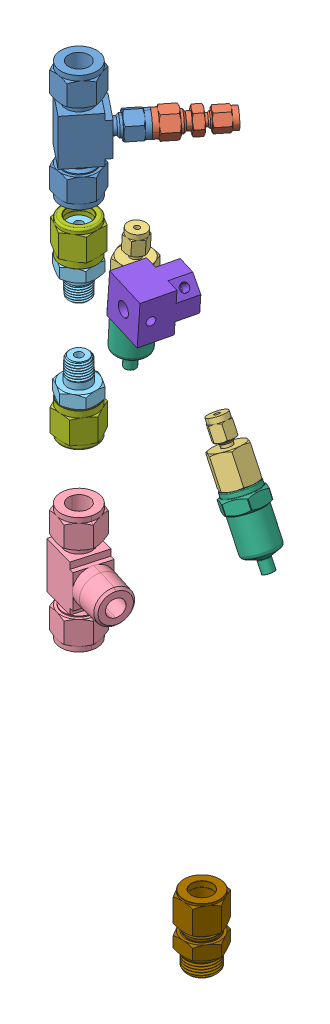
SolidWorks assembly BS2 Lower Fluids Assembly LOx, configuration Default. Lengths in mm.
Overall size (161.41 500.91 102.98).
19 component instances, 14 part files, 96 mates.
Components (placement in the parent):
- -8 MS -4MS -8MS Tee-1: -8 MS -4MS -8MS Tee [Default] at (-23.9548 1051.2282 52.2584) x (0 1 0) z (-0.624096 0 0.781347) size (72.14 22.35 44.65)
- -4 MS to -2 MS.stp-1: -4 MS to -2 MS.stp [Default] at (-4.1397 1087.2962 27.4506) x (0.624096 0 -0.781347) z (0.781347 0 0.624096) size (38.61 14.22 16.42)
- -2 MS to -4 FNPT-1: -2 MS to -4 FNPT [Default] at (38.4704 953.5373 29.1263) x (0.467448 -0.88319 0.038303) z (-0.038303 0.023053 0.999) size (33.53 19.05 22)
- -2 MS to -4 FNPT-2: -2 MS to -4 FNPT [Default] at (-56.112 983.757 -15.9203) x (-0.034482 -0.999152 0.022511) z (-0.575272 0.038262 0.817067) size (33.53 19.05 22)
- -8MS -8 MNPT -8MS Tee.stp-2: -8MS -8 MNPT -8MS Tee.stp [Default] at (-23.9548 886.0647 52.2584) x (0 -1 0) z (-0.962728 0 -0.27047) size (72.14 22.35 45.92)
- BallValve -8FNPT No handle-4: BallValve -8FNPT No handle [46495K21] at (21.8363 849.9967 65.123) x (0.028527 -0.994422 -0.10154) z (0.962728 0 0.27047) (suppressed, hidden)
- -8 MAN -8 MNPT-1: -8 MAN -8 MNPT [50715K116] at (-23.9548 1016.5413 52.2584) x (1 0 0) z (0 1 0) size (20.64 23.83 39.3)
- -8 MAN -8 MNPT-2: -8 MAN -8 MNPT [50715K116] at (-23.9548 946.1515 52.2584) x (1 0 0) z (0 -1 0) size (20.64 23.83 39.3)
- -8 Bottom Tank-1: -8 Bottom Tank [Default] at (-23.9548 863.2047 52.2584) x (0.033836 0 -0.999427) z (0.999427 0 0.033836) (suppressed, hidden)
- -8 Bottom Tank Post MV-1: -8 Bottom Tank Post MV [Default] at (-23.9548 1035.9882 52.2584) x (0.222246 0 -0.974991) z (0.974991 0 0.222246) (suppressed, hidden)
- PT -4MNPT-1: PT -4MNPT [Default] at (59.285 914.2106 30.8319) x (-0.467448 0.88319 -0.038303) z (0.475074 0.214432 -0.853418) size (56.32 25.42 22.23)
- PT -4MNPT-2: PT -4MNPT [Default] at (-57.6475 939.2668 -14.9179) x (0.034482 0.999152 -0.022511) z (0.950092 -0.025784 0.310902) size (56.32 25.42 22.23)
- Defined Kinetrol-2: Defined Kinetrol [Default] at (-4.5128 981.3338 -29.4755) x (-0.969139 0.091601 -0.228865) z (-0.229831 0 0.973231) (suppressed, hidden)
- -8 Bottom Tank to MV-1: -8 Bottom Tank to MV [Default] at (0 641.7628 0) x (0.909045 0 0.416698) z (-0.416698 0 0.909045) (suppressed, hidden)
- BallValve -8FNPT No handle-1: BallValve -8FNPT No handle [46495K21] at (-23.9548 981.3464 52.2584) x (-0.973231 0 -0.229831) z (0 -1 0) (suppressed, hidden)
- -8AN Al Nut-1: -8AN Al Nut [2227K63] at (-23.9548 1019.1924 52.2584) x (0.999966 0 -0.00829) z (0 1 0) size (22.23 25.66 21.56)
- -8AN Al Nut-4: -8AN Al Nut [2227K63] at (-23.9548 943.5004 52.2584) x (0.832606 0 0.553865) z (0 -1 0) size (22.23 25.66 21.56)
- kincon_2_0.75Inch-2: kincon_2_0.75Inch [Default] at (-11.3798 981.3464 -0.9912) x (-0.748323 -0.639362 -0.176718) z (-0.622247 0.768906 -0.146945) size (35.92 31.75 35.92)
- -8 Swage to ORB-1: -8 Swage to ORB [5182K867] at (0 664.6227 0) x (-0.837169 0 -0.546944) z (0 1 0) size (22.23 25.66 42.16)
Mates (geometry in assembly coordinates):
- Coincident12: coincident anti-aligned: cone of Recovery Complete CAD-1/Strength Test Drogue Pods-1 through (0 -2736.5654 0) axis (0 -1 0); circle of COTS Tangent Ogive Nose Cone with metal tip - 8 inch-1/Tangent_Ogive_Nosecone_01-1
- Concentric22: concentric aligned: cylinder of Upper Prop Skin-2 through (0 -990.6 0) axis (0 -1 0) radius 101.6; cylinder of Coupler-3 through (0 -1866.9 0) axis (0 -1 0) radius 98.425
- Concentric24: concentric aligned: cylinder of COPV skin-2 through (0 -1905 0) axis (0 -1 0) radius 101.6; cylinder of Upper Prop Skin-2 through (0 -990.6 0) axis (0 -1 0) radius 101.6
- Coincident21: coincident anti-aligned: plane of COPV skin-2 through (0 -1905 0) normal (0 1 0); plane of Upper Prop Skin-2 through (0 -1905 0) normal (0 -1 0)
- Distance2: distance = 38.1 mm aligned: plane of Upper Prop Skin-2 through (0 -1905 0) normal (0 -1 0); plane of Coupler-3 through (0 -1943.1 0) normal (0 -1 0)
- Tangent2: tangent anti-aligned: cylinder of Upper Prop Skin-2 through (0 -990.6 0) axis (0 -1 0) radius 101.6; plane of 92620A408_Zinc Yellow-Chromate Plated Hex Head Screw-1 through (47.7776 -954.5521 89.7332) normal (-0.5 0 -0.866025)
- Parallel3: parallel anti-aligned: cylinder of Upper Prop Skin-2 through (-143.466 -1885.95 7.9145) axis (0.998482 0 -0.055083) radius 1.5875; cylinder of Coupler-3 through (98.2756 -1885.95 -5.4215) axis (-0.998482 0 0.055083) radius 1.5875
- Concentric52: concentric anti-aligned: cylinder of BallValve -8FNPT No handle-1 through (-23.9548 995.8244 52.2584) axis (0 -1 0) radius 6.35; cylinder of -8FS -8MAN-1 through (-143.6616 977.0926 222.6164) axis (0 -1 0) radius 4.9657
- Coincident46: coincident anti-aligned: plane of BallValve -8FNPT No handle-1 through (-23.9548 1011.3184 52.2584) normal (0 1 0); plane of -8FS -8MAN-1 through (-143.3874 1004.2706 209.7877) normal (0 1 0)
- Coincident47: coincident aligned: circle of -8FS -8MAN-1; cone of -8AN Al Nut-1 through (-23.9548 1019.1924 52.2584) axis (0 -1 0)
- Concentric59: concentric aligned: cylinder of BallValve -8FNPT No handle-2 through (89.6282 874.3013 -241.9648) axis (0.042846 0.996573 -0.070751) radius 6.35; cylinder of -8FS -8MAN-3 through (103.855 914.3674 -250.7408) axis (-0.007638 0.99997 0.001301) radius 4.9657
- Coincident59: coincident anti-aligned: plane of BallValve -8FNPT No handle-2 through (94.7432 919.527 -230.0938) normal (0.042846 0.996573 -0.070751); plane of -8FS -8MAN-3 through (107.2777 887.2309 -263.1983) normal (0.007638 -0.99997 -0.001301)
- Coincident60: coincident anti-aligned: plane of BallValve -8FNPT No handle-2 through (88.9643 858.8604 -240.8686) normal (-0.042846 -0.996573 0.070751); plane of -8FS -8MAN-2 through (104.8256 827.267 -263.682) normal (-0.007638 0.99997 0.001301)
- Concentric60: concentric anti-aligned: cylinder of BallValve -8FNPT No handle-2 through (89.6282 874.3013 -241.9648) axis (0.042846 0.996573 -0.070751) radius 6.35; cylinder of -8FS -8MAN-2 through (104.7279 800.0708 -250.8894) axis (0.007638 -0.99997 -0.001301) radius 4.9657
- Concentric61: concentric anti-aligned: cylinder of -8AN Al Nut-2 through (88.6269 851.0134 -240.3115) axis (0.042846 0.996573 -0.070751) radius 8.7517; cylinder of -8FS -8MAN-2 through (104.7279 800.0708 -250.8894) axis (0.007638 -0.99997 -0.001301) radius 4.9657
- Concentric62: concentric anti-aligned: cylinder of -8AN Al Nut-3 through (91.8701 926.4461 -245.6668) axis (-0.042846 -0.996573 0.070751) radius 8.7517; cylinder of -8FS -8MAN-3 through (103.855 914.3674 -250.7408) axis (-0.007638 0.99997 0.001301) radius 4.9657
- Coincident61: coincident anti-aligned: plane of -8AN Al Nut-3 through (82.9788 926.1718 -254.9145) normal (-0.042846 -0.996573 0.070751); plane of -8FS -8MAN-3 through (107.2214 894.5967 -263.1887) normal (-0.007638 0.99997 0.001301)
- Coincident62: coincident anti-aligned: circle of -8AN Al Nut-2; cone of -8FS -8MAN-2 through (104.5727 820.3905 -250.863) axis (0.007638 -0.99997 -0.001301)
- Concentric68: concentric anti-aligned: cylinder of BallValve -8FNPT No handle-1 through (-23.9548 995.8244 52.2584) axis (0 -1 0) radius 6.35; cylinder of -8FS -8MAN-4 through (-143.6616 1044.4026 222.6164) axis (0 -1 0) radius 4.9657
- Coincident64: coincident aligned: plane of BallValve -8FNPT No handle-1 through (-20.4192 951.3744 37.2869) normal (0 -1 0); circle of -8FS -8MAN-4
- Concentric69: concentric aligned: cylinder of -8AN Al Nut-4 through (-23.9548 943.5004 52.2584) axis (0 1 0) radius 8.7517; cylinder of -8FS -8MAN-4 through (-143.6616 1044.4026 222.6164) axis (0 -1 0) radius 4.9657
- Coincident65: coincident anti-aligned: plane of -8AN Al Nut-4 through (-31.0618 943.5004 62.9421) normal (0 1 0); plane of -8FS -8MAN-4 through (-138.8376 1071.5806 210.7261) normal (0 1 0)
- Concentric72: concentric aligned: circle of BallValve -8FNPT No handle-2; circle of kincon_2_0.75Inch-1
- Coincident85: coincident anti-aligned: plane of BallValve -8FNPT No handle-2 through (94.7957 884.407 -220.1681) normal (0.208698 0.060326 0.976118); plane of kincon_2_0.75Inch-1 through (95.0411 890.1151 -220.5733) normal (-0.208698 -0.060326 -0.976118)
- Concentric73: concentric aligned: circle of BallValve -8FNPT No handle-1; circle of kincon_2_0.75Inch-2
- Coincident86: coincident anti-aligned: plane of BallValve -8FNPT No handle-1 through (-18.6769 987.0741 29.9089) normal (0.229831 0 -0.973231); plane of kincon_2_0.75Inch-2 through (-18.6769 981.3464 29.9089) normal (-0.229831 0 0.973231)
- Tangent3: tangent anti-aligned: cylinder of Upper Prop Skin-2 through (0 -990.6 0) axis (0 -1 0) radius 101.6; plane of 92220A183_Alloy Steel Low-Profile Socket Head Screw-1 through (89.7349 -1004.0731 47.69) normal (-0.892252 0 -0.451538)
- Coincident103: coincident anti-aligned: line of Defined Kinetrol-2 through (-8.5702 981.4187 12.7216) axis (-0.622247 0.768906 -0.146945); line of kincon_2_0.75Inch-2 through (-12.7344 986.5644 11.7382) axis (0.622247 -0.768906 0.146945)
- Concentric84: concentric aligned: cylinder of -8AN Al Tee-1 through (144.1547 917.8727 -221.5336) axis (0 0 -1) radius 4.9657; cylinder of -8AN Al Nut-5 through (144.1547 917.8727 -281.7376) axis (0 0 -1) radius 8.7517
- Concentric89: concentric anti-aligned: cylinder of BallValve -8FNPT No handle-3 through (144.457 782.0311 -215.5778) axis (-0.94691 0.017922 -0.320998) radius 6.35; cylinder of -8MS -8 MNPT -8MS Tee.stp-1 through (107.5778 782.7291 -228.0797) axis (0.94691 -0.017922 0.320998) radius 5.207
- Coincident109: coincident aligned: cone of BallValve -8FNPT No handle-3 through (117.0383 782.5501 -224.8726) axis (0.94691 -0.017922 0.320998); cone of -8MS -8 MNPT -8MS Tee.stp-1 through (116.1419 782.567 -225.1765) axis (0.94691 -0.017922 0.320998)
- Concentric90: concentric aligned: cylinder of -8 Al Top Tank to MV-1 through (82.8344 716.2834 -230.7465) axis (0.042846 0.996573 -0.070751) radius 6.35; cylinder of -8MS -8 MNPT -8MS Tee.stp-1 through (84.6533 758.5895 -233.7499) axis (0.042846 0.996573 -0.070751) radius 6.35
- Concentric91: concentric aligned: cylinder of -8 Bottom Tank to MV-1 through (-23.9548 785.9887 52.2584) axis (0 1 0) radius 6.35; cylinder of -8MS -8 MNPT -8MS Tee.stp-2 through (-23.9548 825.3587 52.2584) axis (0 1 0) radius 6.35
- Coincident110: coincident anti-aligned: plane of -8 Bottom Tank to MV-1 through (-23.9548 836.7887 52.2584) normal (0 1 0); plane of -8MS -8 MNPT -8MS Tee.stp-2 through (-23.9548 836.7887 52.2584) normal (0 -1 0)
- Coincident111: coincident aligned: cone of -8MS -8 MNPT -8MS Tee.stp-2 through (6.9866 849.9967 60.9511) axis (0.962728 0 0.27047); cone of BallValve -8FNPT No handle-4 through (7.8979 849.9967 61.2071) axis (0.962728 0 0.27047)
- Concentric92: concentric anti-aligned: cylinder of -8AN Al Nut-4 through (-23.9548 943.5004 52.2584) axis (0 1 0) radius 8.7517; cylinder of -8 MAN -8 MNPT-2 through (-23.9548 926.7047 52.2584) axis (0 -1 0) radius 2.413
- Concentric93: concentric aligned: cylinder of BallValve -8FNPT No handle-1 through (-23.9548 995.8244 52.2584) axis (0 -1 0) radius 6.35; cylinder of -8 MAN -8 MNPT-2 through (-23.9548 926.7047 52.2584) axis (0 -1 0) radius 2.413
- Coincident114: coincident anti-aligned: plane of -8AN Al Nut-4 through (-31.0618 943.5004 62.9421) normal (0 1 0); plane of -8 MAN -8 MNPT-2 through (-23.9548 943.5004 60.4461) normal (0 -1 0)
- Coincident115: coincident anti-aligned: plane of BallValve -8FNPT No handle-1 through (-20.4192 951.3744 37.2869) normal (0 -1 0); plane of -8 MAN -8 MNPT-2 through (-23.9548 951.3744 62.5771) normal (0 1 0)
- Coincident117: coincident anti-aligned: plane of BallValve -8FNPT No handle-1 through (-23.9548 1011.3184 52.2584) normal (0 1 0); plane of -8 MAN -8 MNPT-1 through (-23.9548 1011.3184 41.9396) normal (0 -1 0)
- Concentric95: concentric anti-aligned: cylinder of BallValve -8FNPT No handle-1 through (-23.9548 995.8244 52.2584) axis (0 -1 0) radius 6.35; cylinder of -8 MAN -8 MNPT-1 through (-23.9548 1035.9882 52.2584) axis (0 1 0) radius 2.413
- Coincident118: coincident anti-aligned: plane of -8AN Al Nut-1 through (-24.0612 1019.1924 39.4272) normal (0 -1 0); plane of -8 MAN -8 MNPT-1 through (-23.9548 1019.1924 44.0707) normal (0 1 0)
- Concentric96: concentric anti-aligned: cylinder of -8AN Al Nut-1 through (-23.9548 1019.1924 52.2584) axis (0 -1 0) radius 8.7517; cylinder of -8 MAN -8 MNPT-1 through (-23.9548 1035.9882 52.2584) axis (0 1 0) radius 2.413
- Coincident119: coincident anti-aligned: plane of BallValve -8FNPT No handle-2 through (94.7432 919.527 -230.0938) normal (0.042846 0.996573 -0.070751); plane of -8 MAN -8 MNPT-4 through (91.5935 917.8657 -255.4022) normal (-0.042846 -0.996573 0.070751)
- Coincident120: coincident anti-aligned: plane of BallValve -8FNPT No handle-2 through (88.9643 858.8604 -240.8686) normal (-0.042846 -0.996573 0.070751); plane of -8 MAN -8 MNPT-3 through (94.5107 858.0072 -249.528) normal (0.042846 0.996573 -0.070751)
- Concentric97: concentric anti-aligned: cylinder of BallValve -8FNPT No handle-2 through (89.6282 874.3013 -241.9648) axis (0.042846 0.996573 -0.070751) radius 6.35; cylinder of -8 MAN -8 MNPT-3 through (87.9073 834.2752 -239.1232) axis (-0.042846 -0.996573 0.070751) radius 2.413
- Concentric98: concentric aligned: cylinder of BallValve -8FNPT No handle-2 through (89.6282 874.3013 -241.9648) axis (0.042846 0.996573 -0.070751) radius 6.35; cylinder of -8 MAN -8 MNPT-4 through (92.5897 943.1843 -246.8551) axis (0.042846 0.996573 -0.070751) radius 2.413
- Concentric99: concentric anti-aligned: cylinder of -8AN Al Nut-2 through (88.6269 851.0134 -240.3115) axis (0.042846 0.996573 -0.070751) radius 8.7517; cylinder of -8 MAN -8 MNPT-3 through (87.9073 834.2752 -239.1232) axis (-0.042846 -0.996573 0.070751) radius 2.413
- Concentric100: concentric anti-aligned: cylinder of -8AN Al Nut-3 through (91.8701 926.4461 -245.6668) axis (-0.042846 -0.996573 0.070751) radius 8.7517; cylinder of -8 MAN -8 MNPT-4 through (92.5897 943.1843 -246.8551) axis (0.042846 0.996573 -0.070751) radius 2.413
- Coincident121: coincident anti-aligned: plane of -8AN Al Nut-3 through (82.9788 926.1718 -254.9145) normal (-0.042846 -0.996573 0.070751); plane of -8 MAN -8 MNPT-4 through (91.9184 925.8642 -253.8337) normal (0.042846 0.996573 -0.070751)
- Coincident122: coincident anti-aligned: plane of -8AN Al Nut-2 through (98.1003 849.9959 -248.9063) normal (0.042846 0.996573 -0.070751); plane of -8 MAN -8 MNPT-3 through (93.0279 850.3364 -247.1826) normal (-0.042846 -0.996573 0.070751)
- Concentric101: concentric aligned: cylinder of -8MS -8 MNPT -8MS Tee.stp-1 through (86.7646 807.6966 -237.2363) axis (-0.042846 -0.996573 0.070751) radius 6.35; cylinder of -8 Top Tank Fill to MV-1 through (87.9073 834.2752 -239.1232) axis (-0.042846 -0.996573 0.070751) radius 5.9808
- Coincident124: coincident anti-aligned: plane of -8 Al Top Tank to MV-1 through (85.143 769.9803 -234.5586) normal (0.042846 0.996573 -0.070751); plane of -8MS -8 MNPT -8MS Tee.stp-1 through (85.143 769.9803 -234.5586) normal (-0.042846 -0.996573 0.070751)
- Coincident127: coincident anti-aligned: plane of -8MS -8 MNPT -8MS Tee.stp-1 through (86.2748 796.3058 -236.4276) normal (0.042846 0.996573 -0.070751); plane of -8 Top Tank Fill to MV-1 through (86.2748 796.3058 -236.4276) normal (-0.042846 -0.996573 0.070751)
- Concentric102: concentric anti-aligned: cylinder of -8AN Al Nut-2 through (88.6269 851.0134 -240.3115) axis (0.042846 0.996573 -0.070751) radius 7.239; cylinder of -8 Top Tank Fill to MV-1 through (87.9073 834.2752 -239.1232) axis (-0.042846 -0.996573 0.070751) radius 5.9808
- Concentric103: concentric anti-aligned: cylinder of -8MS -8 MNPT -8MS Tee.stp-2 through (-23.9548 874.6347 52.2584) axis (0 -1 0) radius 6.35; cylinder of -8 Bottom Tank-1 through (-23.9548 863.2047 52.2584) axis (0 1 0) radius 5.9805
- Coincident129: coincident anti-aligned: plane of -8MS -8 MNPT -8MS Tee.stp-2 through (-23.9548 863.2047 52.2584) normal (0 1 0); plane of -8 Bottom Tank-1 through (-23.9548 863.2047 52.2584) normal (0 -1 0)
- Concentric104: concentric anti-aligned: cylinder of -8 MAN -8 MNPT-2 through (-23.9548 926.7047 52.2584) axis (0 -1 0) radius 2.413; cylinder of -8 Bottom Tank-1 through (-23.9548 863.2047 52.2584) axis (0 1 0) radius 5.9805
- Coincident130: coincident anti-aligned: plane of -8 MAN -8 MNPT-2 through (-23.9548 926.7047 54.6714) normal (0 -1 0); plane of -8 Bottom Tank-1 through (-23.9548 926.7047 52.2584) normal (0 1 0)
- Coincident131: coincident anti-aligned: line of Defined Kinetrol-2 through (-14.0831 975.5845 11.4197) axis (0.748323 0.639362 0.176718); line of kincon_2_0.75Inch-2 through (-9.2203 979.7391 12.5681) axis (-0.748323 -0.639362 -0.176718)
- Coincident142: coincident anti-aligned: line of Defined Kinetrol-1 through (104.6495 890.9129 -203.1609) axis (-0.632602 -0.752842 0.18178); line of kincon_2_0.75Inch-1 through (100.5387 886.0208 -201.9796) axis (0.632602 0.752842 -0.18178)
- Coincident141: coincident anti-aligned: line of Defined Kinetrol-1 through (98.8898 885.3922 -201.5882) axis (-0.745828 0.655431 0.118955); line of kincon_2_0.75Inch-1 through (93.8986 889.7784 -200.7922) axis (0.745828 -0.655431 -0.118955)
- Concentric105: concentric anti-aligned: cylinder of -8AN Al Nut-3 through (91.8701 926.4461 -245.6668) axis (-0.042846 -0.996573 0.070751) radius 8.7517; cylinder of -8FS -8MAN-5 through (-18.2973 1099.6198 -57.8209) axis (-0.006569 0.999978 0.001061) radius 8.322
- Coincident144: coincident anti-aligned: plane of -8 MAN -8 MNPT-3 through (89.2043 834.0757 -241.1482) normal (-0.042846 -0.996573 0.070751); plane of -8 Top Tank Fill to MV-1 through (87.9073 834.2752 -239.1232) normal (0.042846 0.996573 -0.070751)
- Concentric106: concentric anti-aligned: cylinder of -8 MAN -8 MNPT-4 through (92.5897 943.1843 -246.8551) axis (0.042846 0.996573 -0.070751) radius 2.413; cylinder of -8 Top Tank Post MV-1 through (96.9429 1044.4361 -254.0434) axis (-0.042846 -0.996573 0.070751) radius 6.35
- Coincident145: coincident anti-aligned: plane of -8 MAN -8 MNPT-4 through (92.6039 943.0128 -249.262) normal (0.042846 0.996573 -0.070751); plane of -8 Top Tank Post MV-1 through (92.5897 943.1843 -246.8551) normal (-0.042846 -0.996573 0.070751)
- Concentric107: concentric aligned: cylinder of -8 MAN -8 MNPT-1 through (-23.9548 1035.9882 52.2584) axis (0 1 0) radius 2.413; cylinder of -8 Bottom Tank Post MV-1 through (-23.9548 1035.9882 52.2584) axis (0 1 0) radius 6.35
- Coincident146: coincident anti-aligned: plane of -8 MAN -8 MNPT-1 through (-23.9548 1035.9882 49.8454) normal (0 1 0); plane of -8 Bottom Tank Post MV-1 through (-23.9548 1035.9882 52.2584) normal (0 -1 0)
- Concentric108: concentric aligned: cylinder of -8 Top Tank Post MV-1 through (96.9429 1044.4361 -254.0434) axis (-0.042846 -0.996573 0.070751) radius 6.35; cylinder of -8s Tee-2 through (-17.8835 1036.6403 -57.8877) axis (0.006569 -0.999978 -0.001061) radius 6.35
- Concentric109: concentric anti-aligned: cylinder of -8 Bottom Tank Post MV-1 through (-23.9548 1035.9882 52.2584) axis (0 1 0) radius 6.35; cylinder of -8s Tee-1 through (-23.9548 1051.2282 52.2584) axis (0 -1 0) radius 6.35
- Coincident149: coincident anti-aligned: plane of -8 Bottom Tank Post MV-1 through (-23.9548 1074.0882 52.2584) normal (0 1 0); plane of -8s Tee-1 through (-20.4836 1074.0882 57.5756) normal (0 -1 0)
- Concentric110: concentric anti-aligned: cylinder of -8 MS to -4 FNPT.stp-2 through (-74.7768 930.2968 -13.754) axis (0.034482 0.999152 -0.022511) radius 6.35; cylinder of PT -4MNPT-2 through (-56.7509 965.2447 -15.5032) axis (-0.034482 -0.999152 0.022511) radius 6.858
- Coincident150: coincident anti-aligned: plane of -8 MS to -4 FNPT.stp-2 through (-73.9532 918.9573 -8.0435) normal (-0.034482 -0.999152 0.022511); plane of PT -4MNPT-2 through (-57.2682 950.2574 -15.1656) normal (0.034482 0.999152 -0.022511)
- Concentric111: concentric anti-aligned: cylinder of -8 MS to -4 FNPT.stp-1 through (48.2965 933.7955 30.9286) axis (-0.467448 0.88319 -0.038303) radius 6.35; cylinder of PT -4MNPT-1 through (47.1313 937.1736 29.836) axis (0.467448 -0.88319 0.038303) radius 6.858
- Coincident151: coincident anti-aligned: plane of -8 MS to -4 FNPT.stp-1 through (50.9847 922.5024 36.1353) normal (0.467448 -0.88319 0.038303); plane of PT -4MNPT-1 through (54.143 923.9257 30.4105) normal (-0.467448 0.88319 -0.038303)
- Concentric112: concentric aligned: cylinder of -8s Tee-2 through (-21.1752 1072.6493 -21.9111) axis (-0.084693 -0.001613 0.996406) radius 6.35; cylinder of -8 MV to PT-1 through (-19.2391 1072.6862 -44.6889) axis (-0.084693 -0.001613 0.996406) radius 5.969
- Coincident152: coincident anti-aligned: plane of -8 Top Tank Post MV-1 through (96.9429 1044.4361 -254.0434) normal (0.042846 0.996573 -0.070751); plane of -8s Tee-2 through (-17.4959 1059.51 -64.1907) normal (0.006569 -0.999978 -0.001061)
- Coincident153: coincident anti-aligned: plane of -8s Tee-2 through (-19.1974 1066.3363 -44.6957) normal (-0.084693 -0.001613 0.996406); plane of -8 MV to PT-1 through (-19.2391 1072.6862 -44.6889) normal (0.084693 0.001613 -0.996406)
- Concentric113: concentric aligned: cone of -8 MS to -4 FNPT.stp-1 through (37.3669 954.4458 30.033) axis (0.467448 -0.88319 0.038303); cylinder of -8 MV to PT-1 through (-7.3451 1038.924 26.3693) axis (0.467448 -0.88319 0.038303) radius 6.35
- Coincident154: coincident anti-aligned: plane of -8 MS to -4 FNPT.stp-1 through (40.1476 949.1918 30.2609) normal (-0.467448 0.88319 -0.038303); plane of -8 MV to PT-1 through (40.1476 949.1918 30.2609) normal (0.467448 -0.88319 0.038303)
- Concentric115: concentric aligned: cone of -8 MS to -4 FNPT.stp-2 through (-73.9705 953.6584 -14.2803) axis (-0.034482 -0.999152 0.022511); cylinder of -8 MV to PT-2 through (-70.6723 1049.2285 -16.4335) axis (-0.034482 -0.999152 0.022511) radius 6.35
- Coincident156: coincident anti-aligned: plane of -8 MS to -4 FNPT.stp-2 through (-74.1756 947.7147 -14.1464) normal (0.034482 0.999152 -0.022511); plane of -8 MV to PT-2 through (-74.1756 947.7147 -14.1464) normal (-0.034482 -0.999152 0.022511)
- Concentric119: concentric aligned: cylinder of -8s Tee-1 through (-43.6714 1087.2962 22.0565) axis (-0.54665 0 -0.837361) radius 6.35; cylinder of -8 MV to PT-2 through (-31.175 1087.2962 41.1985) axis (-0.54665 0 -0.837361) radius 6.35
- Coincident157: coincident anti-aligned: plane of -8s Tee-1 through (-31.175 1080.9462 41.1985) normal (-0.54665 0 -0.837361); plane of -8 MV to PT-2 through (-31.175 1087.2962 41.1985) normal (0.54665 0 0.837361)
- Concentric122: concentric aligned: cylinder of -8 Bottom Tank Post MV-1 through (-23.9548 1035.9882 52.2584) axis (0 1 0) radius 6.35; cylinder of -8 MS -4MS -8MS Tee-1 through (-23.9548 1062.6582 52.2584) axis (0 1 0) radius 6.35
- Coincident158: coincident anti-aligned: plane of -8 Bottom Tank Post MV-1 through (-23.9548 1074.0882 52.2584) normal (0 1 0); plane of -8 MS -4MS -8MS Tee-1 through (-23.9548 1074.0882 52.2584) normal (0 -1 0)
- Concentric123: concentric anti-aligned: cylinder of -8 Top Tank Post MV-1 through (96.9429 1044.4361 -254.0434) axis (-0.042846 -0.996573 0.070751) radius 6.35; cylinder of -8 MS -4MS -8MS Tee-2 through (96.4532 1033.0453 -253.2347) axis (0.042846 0.996573 -0.070751) radius 6.35
- Coincident159: coincident anti-aligned: plane of -8 Top Tank Post MV-1 through (96.9429 1044.4361 -254.0434) normal (0.042846 0.996573 -0.070751); plane of -8 MS -4MS -8MS Tee-2 through (96.9429 1044.4361 -254.0434) normal (-0.042846 -0.996573 0.070751)
- Coincident160: coincident anti-aligned: plane of -8 MS -4MS -8MS Tee-1 through (-4.1397 1083.7402 27.4506) normal (0.624096 0 -0.781347); plane of -4 MS to -2 MS.stp-1 through (-1.3613 1087.2962 29.6699) normal (-0.624096 0 0.781347)
- Concentric124: concentric anti-aligned: cylinder of -8 MS -4MS -8MS Tee-1 through (-8.8954 1087.2962 33.4045) axis (-0.624096 0 0.781347) radius 3.175; cylinder of -4 MS to -2 MS.stp-1 through (0.6159 1087.2962 21.4967) axis (0.624096 0 -0.781347) radius 3.175
- Concentric126: concentric anti-aligned: cylinder of PT -4MNPT-1 through (47.1313 937.1736 29.836) axis (0.467448 -0.88319 0.038303) radius 6.858; cone of -2 MS to -4 FNPT-1 through (51.5372 928.8491 30.197) axis (-0.467448 0.88319 -0.038303)
- Coincident162: coincident anti-aligned: plane of PT -4MNPT-1 through (54.143 923.9257 30.4105) normal (-0.467448 0.88319 -0.038303); plane of -2 MS to -4 FNPT-1 through (53.9606 924.0355 35.1683) normal (0.467448 -0.88319 0.038303)
- Coincident163: coincident anti-aligned: plane of PT -4MNPT-2 through (-57.2682 950.2574 -15.1656) normal (0.034482 0.999152 -0.022511); plane of -2 MS to -4 FNPT-2 through (-60.0079 950.4397 -11.2743) normal (-0.034482 -0.999152 0.022511)
- Concentric127: concentric aligned: cylinder of PT -4MNPT-2 through (-57.2682 950.2574 -15.1656) axis (0.034482 0.999152 -0.022511) radius 4; cone of -2 MS to -4 FNPT-2 through (-57.0759 955.8273 -15.291) axis (0.034482 0.999152 -0.022511)
- Concentric128: concentric aligned: cylinder of -8 Bottom Tank to MV-1 through (0 641.7628 0) axis (0 1 0) radius 6.35; cylinder of -8 Swage to ORB-1 through (0 664.6227 0) axis (0 1 0) radius 6.35
- Coincident164: coincident anti-aligned: plane of -8 Bottom Tank to MV-1 through (0 641.7628 0) normal (0 -1 0); plane of -8 Swage to ORB-1 through (-3.4731 641.7628 5.316) normal (0 1 0)
